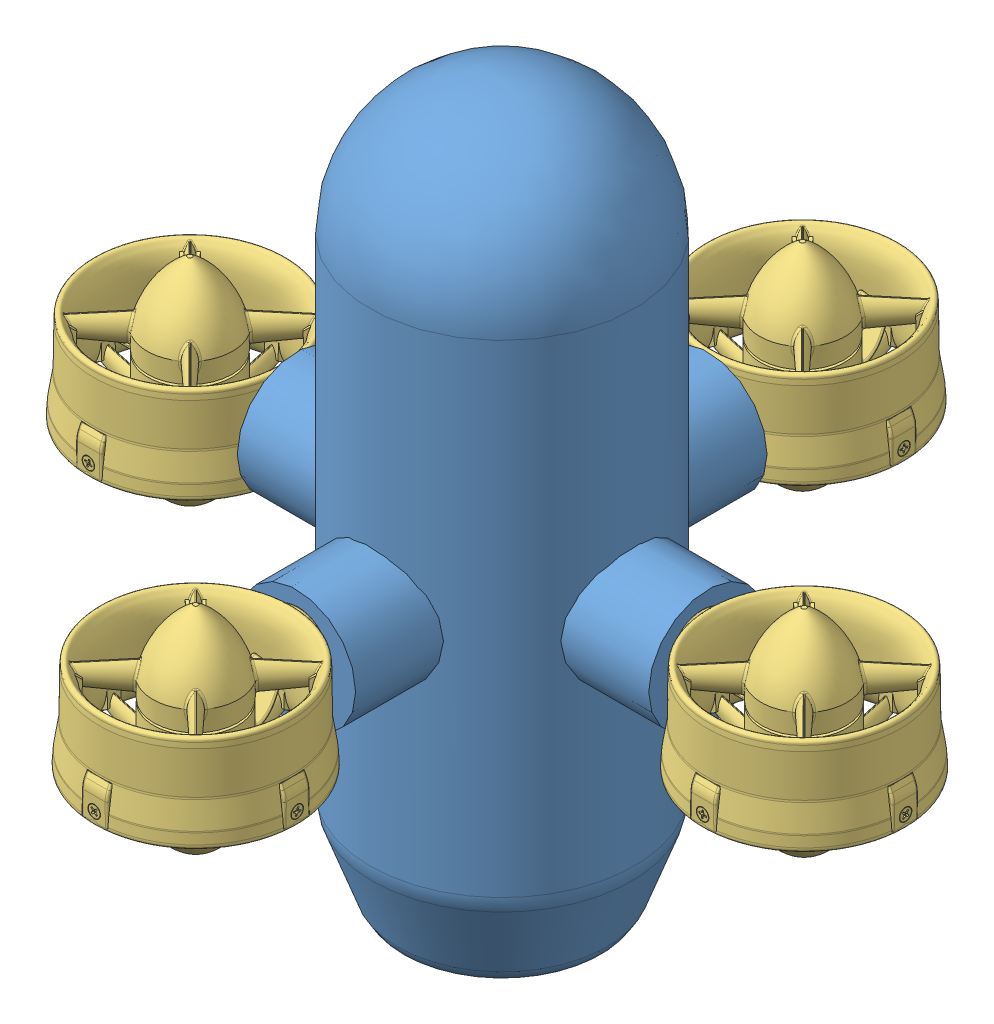
SolidWorks assembly Assem1, configuration Default. Lengths in mm.
Overall size (387.41 340.87 390.41).
6 component instances, 3 part files, 11 mates.
Components (placement in the parent):
- ROV Vol 1 - Copy-1: ROV Vol 1 - Copy [Default] at (184.4238 299.8647 221.6735) size (195.7 340.87 195.7)
- watec902H-1: watec902H [Default] at (184.4238 323.1147 206.6735) size (46.8 36.5 58.1)
- T100-ASM-CCW-THRUSTER-R1-1: T100-ASM-CCW-THRUSTER-R1 [Default] at (40.5738 175.3229 226.3391) x (0 0 -1) z (0 -1 0) size (96.71 97.51 100.86)
- T100-ASM-CCW-THRUSTER-R1-2: T100-ASM-CCW-THRUSTER-R1 [Default] at (331.2738 175.2808 224.9075) x (0 0 1) z (0 -1 0) size (96.71 97.51 100.86)
- T100-ASM-CCW-THRUSTER-R1-3: T100-ASM-CCW-THRUSTER-R1 [Default] at (185.5139 175.4156 368.5235) x (-1 0 0) z (0 -1 0) size (96.71 97.51 100.86)
- T100-ASM-CCW-THRUSTER-R1-4: T100-ASM-CCW-THRUSTER-R1 [Default] at (180.4299 175.596 74.8235) x (1 0 0) z (0 -1 0) size (96.71 97.51 100.86)
Mates (geometry in assembly coordinates):
- Coincident1: coincident anti-aligned: plane of ROV Vol 1 - Copy-1 through (184.4238 173.6647 319.5235) normal (0 0 1); plane of T100-ASM-CCW-THRUSTER-R1-3 through (185.5139 180.6674 319.5235) normal (0 0 -1)
- Coincident2: coincident anti-aligned: plane of ROV Vol 1 - Copy-1 through (282.2738 173.6647 221.6735) normal (1 0 0); plane of T100-ASM-CCW-THRUSTER-R1-2 through (282.2738 180.5325 224.9075) normal (-1 0 0)
- Coincident3: coincident anti-aligned: plane of ROV Vol 1 - Copy-1 through (184.4238 173.6647 123.8235) normal (0 0 -1); plane of T100-ASM-CCW-THRUSTER-R1-4 through (180.4299 180.8477 123.8235) normal (0 0 1)
- Coincident4: coincident anti-aligned: plane of ROV Vol 1 - Copy-1 through (86.5738 173.6647 221.6735) normal (-1 0 0); plane of T100-ASM-CCW-THRUSTER-R1-1 through (86.5738 169.9912 226.3391) normal (1 0 0)
- Parallel1: parallel anti-aligned: plane of ROV Vol 1 - Copy-1 through (230.9113 21.8647 221.6735) normal (0 -1 0); plane of T100-ASM-CCW-THRUSTER-R1-1 through (43.0738 220.602 274.693) normal (0 1 0)
- Parallel2: parallel anti-aligned: plane of ROV Vol 1 - Copy-1 through (230.9113 21.8647 221.6735) normal (0 -1 0); plane of T100-ASM-CCW-THRUSTER-R1-3 through (233.8678 220.6947 366.0235) normal (0 1 0)
- Parallel3: parallel anti-aligned: plane of ROV Vol 1 - Copy-1 through (230.9113 21.8647 221.6735) normal (0 -1 0); plane of T100-ASM-CCW-THRUSTER-R1-2 through (328.7738 220.5599 176.5536) normal (0 1 0)
- Parallel4: parallel anti-aligned: plane of ROV Vol 1 - Copy-1 through (230.9113 21.8647 221.6735) normal (0 -1 0); plane of T100-ASM-CCW-THRUSTER-R1-4 through (132.076 220.8751 77.3235) normal (0 1 0)
- Coincident9: coincident anti-aligned: plane of ROV Vol 1 - Copy-1 through (184.4238 304.8647 284.5397) normal (0 1 0); plane of watec902H-1 through (184.4238 304.8647 232.1735) normal (0 -1 0)
- Distance1: distance = 15 mm aligned: plane of ROV Vol 1 - Copy-1 through (184.4238 299.8647 221.6735) normal (0 0 1); plane of watec902H-1 through (184.4238 323.1147 206.6735) normal (0 0 1)
- Coincident11: coincident aligned: plane of ROV Vol 1 - Copy-1 through (184.4238 299.8647 221.6735) normal (1 0 0); plane of watec902H-1 through (184.4238 323.1147 206.6735) normal (1 0 0)
